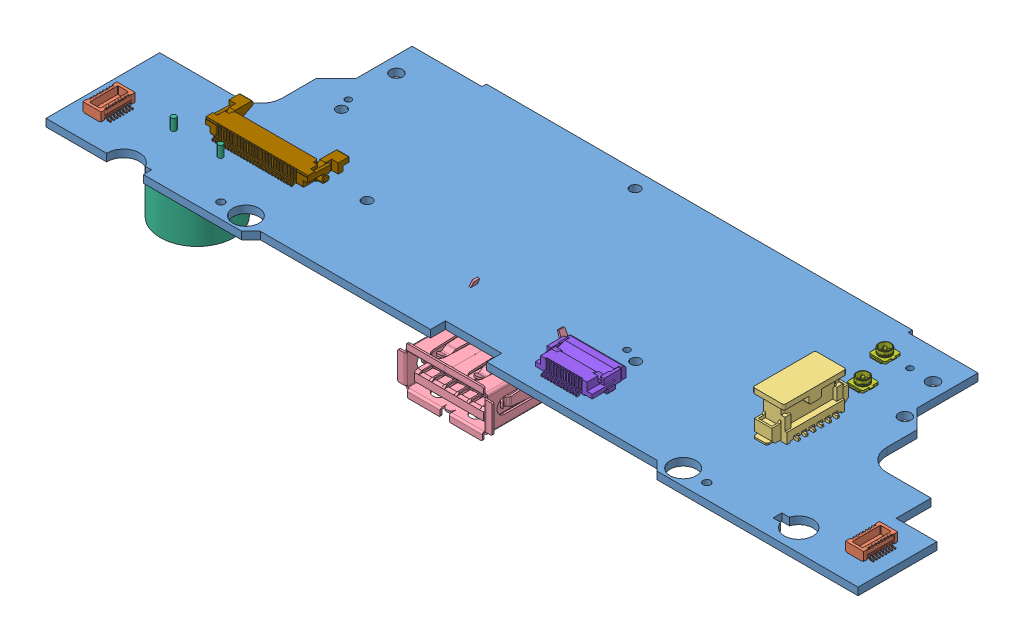
SolidWorks assembly PumaTx_MB assembly, configuration Défaut. Lengths in mm.
Overall size (130 15.9 40.7).
15 component instances, 9 part files, 42 mates.
Components (placement in the parent):
- PumaTx_MB-1: PumaTx_MB [Défaut] at (-94.4326 34.1167 16.1) size (130 1.2 40)
- 500334-0160.stp-1: 500334-0160.stp [Défaut] at (-33.3426 35.4167 13.475) x (0 0 1) z (-1 0 0) size (5.45 1.58 4.2)
- 500334-0160.stp-2: 500334-0160.stp [Défaut] at (-155.3226 35.4167 13.575) x (0 0 1) z (-1 0 0) size (5.45 1.58 4.2)
- 53398-0667.stp-1: 53398-0667.stp [Défaut] at (-56.4826 39.0417 1.375) x (0 0 -1) z (1 0 0) size (12.65 5.7 5.6)
- 692122030100.stp-1: 692122030100.stp [Défaut] at (-94.4336 29.0167 8.04) x (0 0 1) z (0 -1 0) size (17.8 15.1 10.24)
- SKRPABE010.step-1: SKRPABE010.step [Défaut] at (-52.7826 34.1167 2.1) x (0 0 -1) z (-1 0 0) size (4.6 2.5 3.2)
- SKRPABE010.step-2: SKRPABE010.step [Défaut] at (-136.5826 34.1167 2.1) x (0 0 -1) z (-1 0 0) size (4.6 2.5 3.2)
- Buzzer-1: Buzzer [Défaut] at (-143.4826 34.1167 11.3) x (-1 0 0) z (0 0 1) size (11.8 12 11.8)
- U.FL-R-SMT-1_40_.stp-1: U.FL-R-SMT-1_40_.stp [Défaut] at (-55.6326 57.8124 46.7389) x (0 0 -1) z (-1 0 0) size (3 1.25 3.1)
- U.FL-R-SMT-1_40_.stp-2: U.FL-R-SMT-1_40_.stp [Défaut] at (-57.8826 57.8124 40.9389) x (0 0 -1) z (-1 0 0) size (3 1.25 3.1)
- FH12-12S-0.5SH_55_.stp-1: FH12-12S-0.5SH_55_.stp [Défaut] at (-99.6401 -182.6185 3.6222) x (0 1 0) z (-1 0 0) size (2.1 6.4 10.1)
  - FH12-12S-0.5SH_55_ v1.step.stp-1: FH12-12S-0.5SH_55_ v1.step.stp [Défaut] at origin size (2.1 6.4 10.1)
    - AA.step.stp-1: AA.step.stp [Défaut] at (220 -8.1868 -29.65) size (2.1 6.4 10.1)
- FH12A-26S-0.5SH.stp-1: FH12A-26S-0.5SH.stp [Défaut] at (-156.1726 35.7167 -12.3) x (0 1 0) z (-1 0 0) size (2.15 7 17.5)
  - AA.stp-1: AA.stp [Défaut] at (0.15 12.85 -10.595) x (-1 0 0) z (0 0 1) size (2.15 7 17.5)
Mates (geometry in assembly coordinates):
- Coïncidente2: coincident: plane of PumaTx_MB-1 through (-146.3826 35.3167 -1.7) normal (0 1 0); line of 500334-0160.stp-2 through (-153.7026 35.3167 11.74) axis (0 0 1)
- Coïncidente3: coincident anti-aligned: plane of PumaTx_MB-1 through (-146.3826 35.3167 -1.7) normal (0 1 0); plane of 500334-0160.stp-1 through (-35.4426 35.3167 14.64) normal (0 -1 0)
- Coïncidente4: coincident anti-aligned: plane of PumaTx_MB-1 through (-146.3826 35.3167 -1.7) normal (0 1 0); plane of 53398-0667.stp-1 through (-58.0826 35.3167 6.574) normal (0 -1 0)
- Parallèle1: parallel anti-aligned: plane of PumaTx_MB-1 through (-89.9326 35.3167 18.5) normal (-1 0 0); plane of 692122030100.stp-1 through (-87.8836 27.4767 20.4) normal (1 0 0)
- Parallèle2: parallel anti-aligned: plane of PumaTx_MB-1 through (-158.9826 35.3167 20) normal (0 0 1); plane of 500334-0160.stp-2 through (-155.3226 35.4167 10.85) normal (0 0 -1)
- Parallèle3: parallel anti-aligned: plane of PumaTx_MB-1 through (-127.6826 35.3167 20) normal (0 0 1); plane of 500334-0160.stp-1 through (-33.3426 35.4167 10.75) normal (0 0 -1)
- Distance1: distance = 3.7 mm aligned: plane of 500334-0160.stp-2 through (-155.3226 35.4167 16.3) normal (0 0 1); plane of PumaTx_MB-1 through (-158.9826 35.3167 20) normal (0 0 1)
- Distance2: distance = 2.2 mm aligned: plane of PumaTx_MB-1 through (-158.9826 35.3167 1.8) normal (-1 0 0); plane of 500334-0160.stp-2 through (-156.7826 36.8967 10.85) normal (-1 0 0)
- Distance3: distance = 2.9 mm aligned: plane of PumaTx_MB-1 through (-28.9826 35.3167 7.4) normal (1 0 0); plane of 500334-0160.stp-1 through (-31.8826 35.5167 10.75) normal (1 0 0)
- Distance4: distance = 3.8 mm aligned: plane of 500334-0160.stp-1 through (-33.3426 35.4167 16.2) normal (0 0 1); plane of PumaTx_MB-1 through (-28.9826 35.3167 20) normal (0 0 1)
- Coïncidente6: coincident anti-aligned: plane of PumaTx_MB-1 through (-146.3826 34.1167 -1.7) normal (0 -1 0); plane of 692122030100.stp-1 through (-90.4336 34.1167 10.94) normal (0 1 0)
- Parallèle4: parallel aligned: plane of PumaTx_MB-1 through (-46.0826 35.3167 -1.7) normal (1 0 0); plane of 53398-0667.stp-1 through (-54.3826 35.3667 6) normal (1 0 0)
- Distance5: distance = 18.9 mm aligned: plane of 53398-0667.stp-1 through (-54.3826 35.3667 6) normal (1 0 0); plane of PumaTx_MB-1 through (-35.4826 35.3167 7.4) normal (1 0 0)
- Distance6: distance = 11 mm aligned: plane of 53398-0667.stp-1 through (-58.0826 36.1167 7.5) normal (0 0 1); plane of PumaTx_MB-1 through (-62.6826 35.3167 18.5) normal (0 0 1)
- Coïncidente11: coincident: line of 692122030100.stp-1 through (-94.4326 33.7117 20.7) axis (0 -1 0)
- Distance7: distance = 40.7 mm anti-aligned: plane of 692122030100.stp-1 through (-94.4336 29.9367 20.7) normal (0 0 1); plane of PumaTx_MB-1 through (-60.2826 35.3167 -20) normal (0 0 -1)
- Coïncidente12: coincident anti-aligned: plane of PumaTx_MB-1 through (-146.3826 34.1167 -1.7) normal (0 -1 0); plane of SKRPABE010.step-1 through (-51.2826 34.1167 0.1) normal (0 1 0)
- Distance8: distance = 15.8 mm aligned: plane of SKRPABE010.step-1 through (-52.7826 32.6667 4.2) normal (0 0 1); plane of PumaTx_MB-1 through (-28.9826 35.3167 20) normal (0 0 1)
- Distance9: distance = 22.2 mm aligned: plane of SKRPABE010.step-1 through (-51.1826 32.5667 3.46) normal (1 0 0); plane of PumaTx_MB-1 through (-28.9826 35.3167 7.4) normal (1 0 0)
- Coïncidente13: coincident anti-aligned: plane of PumaTx_MB-1 through (-146.3826 34.1167 -1.7) normal (0 -1 0); plane of SKRPABE010.step-2 through (-135.0826 34.1167 0.1) normal (0 1 0)
- Distance10: distance = 15.8 mm aligned: plane of SKRPABE010.step-2 through (-136.5826 32.6667 4.2) normal (0 0 1); plane of PumaTx_MB-1 through (-127.6826 35.3167 20) normal (0 0 1)
- Distance11: distance = 20.8 mm aligned: plane of SKRPABE010.step-2 through (-138.1826 32.5667 3.46) normal (-1 0 0); plane of PumaTx_MB-1 through (-158.9826 35.3167 1.8) normal (-1 0 0)
- Coïncidente14: coincident anti-aligned: plane of PumaTx_MB-1 through (-146.3826 34.1167 -1.7) normal (0 -1 0); plane of Pièce16^PumaTx_MB assembly-1 through (-143.4826 34.1167 11.3) normal (0 1 0)
- Distance14: distance = 8.7 mm: cylinder of Pièce16^PumaTx_MB assembly-1 through (-143.4826 25.1167 11.3) axis (0 1 0) radius 5.9; plane of PumaTx_MB-1 through (-127.6826 35.3167 20) normal (0 0 1)
- Distance15: distance = 9.6 mm: cylinder of Pièce16^PumaTx_MB assembly-1 through (-143.4826 25.1167 11.3) axis (0 1 0) radius 5.9; plane of PumaTx_MB-1 through (-158.9826 35.3167 1.8) normal (-1 0 0)
- Parallèle5: parallel aligned: plane of PumaTx_MB-1 through (-127.6826 35.3167 20) normal (0 0 1); plane of Pièce16^PumaTx_MB assembly-1 through (-143.4826 34.1167 11.7) normal (0 0 1)
- Coïncidente17: coincident anti-aligned: plane of PumaTx_MB-1 through (-146.3826 35.3167 -1.7) normal (0 1 0); plane of U.FL-R-SMT-1_40_.stp-1 through (-56.5317 35.3167 -4.181) normal (0 -1 0)
- Parallèle8: parallel anti-aligned: plane of PumaTx_MB-1 through (-60.2826 35.3167 -20) normal (0 0 -1); plane of U.FL-R-SMT-1_40_.stp-1 through (-55.8326 35.3167 -7) normal (0 0 1)
- Coïncidente18: coincident anti-aligned: plane of PumaTx_MB-1 through (-146.3826 35.3167 -1.7) normal (0 1 0); plane of U.FL-R-SMT-1_40_.stp-2 through (-58.7817 35.3167 -9.981) normal (0 -1 0)
- Parallèle9: parallel aligned: plane of PumaTx_MB-1 through (-60.2826 35.3167 -20) normal (0 0 -1); plane of U.FL-R-SMT-1_40_.stp-2 through (-60.2826 35.3167 -15.6) normal (0 0 -1)
- Distance23: distance = 9.1 mm aligned: plane of U.FL-R-SMT-1_40_.stp-1 through (-55.1826 35.3167 -8.8) normal (1 0 0); plane of PumaTx_MB-1 through (-46.0826 35.3167 -1.7) normal (1 0 0)
- Distance24: distance = 11.6 mm aligned: plane of U.FL-R-SMT-1_40_.stp-2 through (-57.6826 35.3167 -15.6) normal (1 0 0); plane of PumaTx_MB-1 through (-46.0826 35.3167 -1.7) normal (1 0 0)
- Distance25: distance = 4.7 mm: plane of PumaTx_MB-1 through (-60.2826 35.3167 -20) normal (0 0 -1); line of U.FL-R-SMT-1_40_.stp-2 through (-58.9826 36.4967 -15.3) axis (0 -1 0)
- Distance26: distance = 9.5 mm aligned: plane of U.FL-R-SMT-1_40_.stp-1 through (-58.0326 35.3167 -9.8) normal (0 0 -1); plane of PumaTx_MB-1 through (-49.0826 35.3167 -19.3) normal (0 0 -1)
- Coïncidente19: coincident anti-aligned: plane of PumaTx_MB-1 through (-146.3826 35.3167 -1.7) normal (0 1 0); plane of FH12-12S-0.5SH_55_.stp-1/FH12-12S-0.5SH_55_ v1.step.stp-1/AA.step.stp-1 through (-83.3576 35.3167 16.1) normal (0 -1 0)
- Parallèle10: parallel aligned: plane of PumaTx_MB-1 through (-158.9826 35.3167 1.8) normal (-1 0 0); plane of FH12-12S-0.5SH_55_.stp-1/FH12-12S-0.5SH_55_ v1.step.stp-1/AA.step.stp-1 through (-85.2476 37.1167 10.8) normal (-1 0 0)
- Distance27: distance = 55 mm aligned: plane of PumaTx_MB-1 through (-28.9826 35.3167 7.4) normal (1 0 0); plane of FH12-12S-0.5SH_55_.stp-1/FH12-12S-0.5SH_55_ v1.step.stp-1/AA.step.stp-1 through (-83.9826 36.2667 10.5) normal (1 0 0)
- Distance28: distance = 7.7 mm anti-aligned: plane of FH12-12S-0.5SH_55_.stp-1/FH12-12S-0.5SH_55_ v1.step.stp-1/AA.step.stp-1 through (-105.4982 36.274 10.8) normal (0 0 -1); plane of PumaTx_MB-1 through (-62.6826 35.3167 18.5) normal (0 0 1)
- Coïncidente20: coincident: plane of PumaTx_MB-1 through (-146.3826 35.3167 -1.7) normal (0 1 0); plane of FH12A-26S-0.5SH.stp-1/AA.stp-1 through (-142.3476 35.3167 9.226) normal (0 -1 0)
- Parallèle11: parallel: plane of PumaTx_MB-1 through (-158.9826 35.3167 1.8) normal (-1 0 0); plane of FH12A-26S-0.5SH.stp-1/AA.stp-1 through (-144.9476 35.7667 5.576) normal (-1 0 0)
- Distance29: distance = 16 mm: plane of FH12A-26S-0.5SH.stp-1/AA.stp-1 through (-142.9826 35.7667 6.15) normal (1 0 0); plane of PumaTx_MB-1 through (-158.9826 35.3167 1.8) normal (-1 0 0)
- Distance31: distance = 25.3 mm aligned: plane of FH12A-26S-0.5SH.stp-1/AA.stp-1 through (-145.5576 37.1667 6) normal (0 0 -1); plane of PumaTx_MB-1 through (-128.4826 35.3167 -19.3) normal (0 0 -1)
